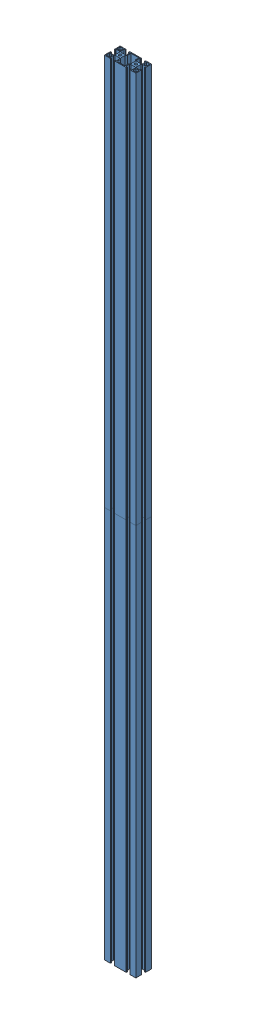
SolidWorks assembly Assem1, configuration Default. Lengths in mm.
Overall size (80 2000 40).
2 component instances, 1 part files, 3 mates.
Components (placement in the parent):
- Basic40x80Bar1m-1: Basic40x80Bar1m [Default] at (-129.5759 104.9039 1316.2024) size (80 1000 40)
- Basic40x80Bar1m-2: Basic40x80Bar1m [Default] at (-129.5759 1104.9039 1316.2024) size (80 1000 40)
Mates (geometry in assembly coordinates):
- Coincident1: coincident: plane of Basic40x80Bar1m-1 through (-129.5759 1104.9039 1316.2024) normal (0 1 0); plane of Basic40x80Bar1m-2 through (-140.8764 1104.9039 1334.2112) normal (0 -1 0)
- Concentric1: concentric: cylinder of Basic40x80Bar1m-1 through (-149.5759 104.9039 1316.2024) axis (0 1 0) radius 3.5; cylinder of Basic40x80Bar1m-2 through (-149.5759 1104.9039 1316.2024) axis (0 1 0) radius 3.5
- Concentric2: concentric aligned: cylinder of Basic40x80Bar1m-1 through (-109.5759 104.9039 1316.2024) axis (0 1 0) radius 3.5; cylinder of Basic40x80Bar1m-2 through (-109.5759 1104.9039 1316.2024) axis (0 1 0) radius 3.5
